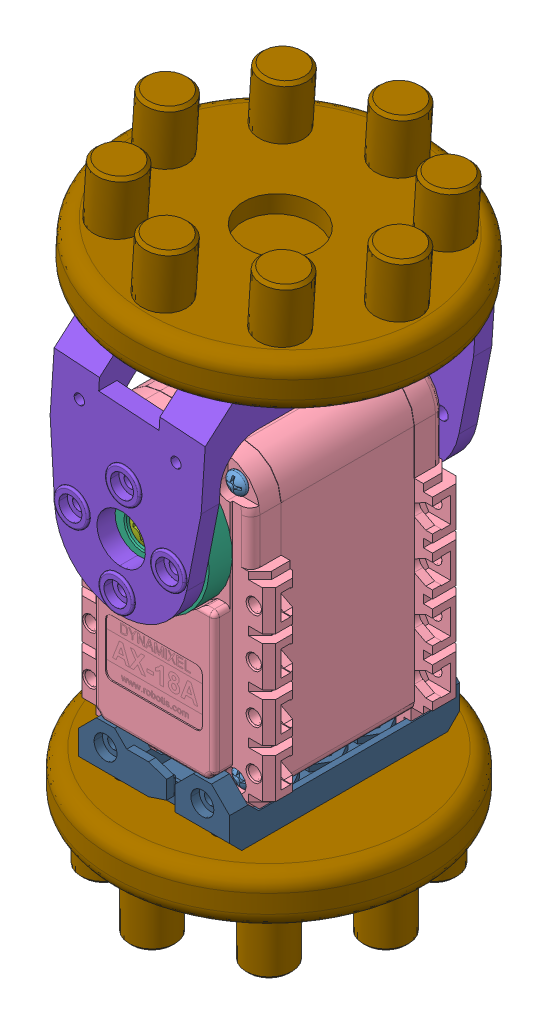
SolidWorks assembly joint, configuration Default. Lengths in mm.
Overall size (63.01 103.17 56.48).
16 component instances, 10 part files, 31 mates.
Components (placement in the parent):
- Cover Screws^joint-8: Cover Screws^joint [Défaut] at (-252.3267 41.8937 41.7384) x (0 1 0) z (1 0 0) size (3.5 30.7 3.5) (virtual)
- Insert M3^joint-2: Insert M3^joint [Défaut] at (-242.8267 33.3937 8.8384) x (-1 0 0) z (0 1 0) size (4.98 7 4.98) (virtual)
- Cover Screws^joint-9: Cover Screws^joint [Défaut] at (-232.3267 0.3937 41.7384) x (0 1 0) z (1 0 0) size (3.5 30.7 3.5) (virtual)
- 3 Pins Connector^joint-3: 3 Pins Connector^joint [Défaut] at (-237.7767 18.2037 17.4884) x (1 0 0) z (0 1 0) size (9.9 9.43 4.9) (virtual)
- Cover Screws^joint-10: Cover Screws^joint [Défaut] at (-233.3267 41.8937 41.7384) x (0 1 0) z (1 0 0) size (3.5 30.7 3.5) (virtual)
- 3 Pins Connector^joint-4: 3 Pins Connector^joint [Défaut] at (-247.7767 18.2037 17.4884) x (1 0 0) z (0 1 0) size (9.9 9.43 4.9) (virtual)
- Body^joint-2: Body^joint [Défaut] at (-242.8267 33.3937 27.2384) size (32 50.04 38.37) (virtual)
- Horn Assembly^joint-2: Horn Assembly^joint [Default] at (-242.8267 33.3937 48.1184) x (-1 0 0) z (0 0 1) size (22 22 9.6) (virtual)
  - Wheel Gear^Horn Assembly_joint-1: Wheel Gear^Horn Assembly_joint [Défaut] at (0 0 -22.94) size (6.5 6.5 5.51) (virtual)
  - Horn^Horn Assembly_joint-1: Horn^Horn Assembly_joint [Défaut] at (0 0 -1.84) x (0 -1 0) z (0 0 1) size (22 22 6.7) (virtual)
  - BHS M2x8^Horn Assembly_joint-1: BHS M2x8^Horn Assembly_joint [Défaut] at (0 0 -1.39) x (1 0 0) z (0 -1 0) size (5.5 9.6 5.5) (virtual)
- Cover Screws^joint-11: Cover Screws^joint [Défaut] at (-253.3267 0.3937 41.7384) x (0 1 0) z (1 0 0) size (3.5 30.7 3.5) (virtual)
- FP04-F2.stp-3: FP04-F2.stp [Default] at (-243.3649 33.4118 27.1184) x (0 0 1) z (0.067269 0.997735 0) size (48.8 25 37)
- servo_module-8: servo_module [Default] at (-242.8267 -16.1063 27.2384) size (56.36 17 56.36)
- servo_module-9: servo_module [Default] at (-241.0777 67.3348 27.1184) x (-0.997735 0.067269 0) z (0 0 1) size (56.36 17 56.36)
- FP04-F3.stp-2: FP04-F3.stp [Default] at (-242.8267 -8.1063 27.2384) size (25 9 38)
Mates (geometry in assembly coordinates):
- Concentric29: concentric: cylinder of FP04-F2.stp-3 through (-233.634 58.8147 43.1184) axis (0.067269 0.997735 0) radius 1.05; cylinder of servo_module-9 through (-233.2304 64.8011 43.1184) axis (-0.067269 -0.997735 0) radius 1.15
- Distance4: distance = 1.88 mm aligned: plane of Horn Assembly^Dynamixel AX-18A-2/Horn^Horn Assembly_Dynamixel AX-18A-1 through (-242.8267 33.3937 48.1184) normal (0 0 1); plane of Body^Dynamixel AX-18A-2 through (-242.8267 33.3937 46.2384) normal (0 0 1)
- Concentric30: concentric anti-aligned: cylinder of Cover Screws^Dynamixel AX-18A-8 through (-252.3267 41.8937 42.9134) axis (0 0 -1) radius 0.8; cylinder of Body^Dynamixel AX-18A-2 through (-252.3267 41.8937 46.2384) axis (0 0 1) radius 1.035
- Concentric31: concentric anti-aligned: cylinder of Cover Screws^Dynamixel AX-18A-9 through (-232.3267 0.3937 42.9134) axis (0 0 -1) radius 0.8; cylinder of Body^Dynamixel AX-18A-2 through (-232.3267 0.3937 46.2384) axis (0 0 1) radius 1.035
- Concentric32: concentric anti-aligned: cylinder of Cover Screws^Dynamixel AX-18A-10 through (-233.3267 41.8937 42.9134) axis (0 0 -1) radius 0.8; cylinder of Body^Dynamixel AX-18A-2 through (-233.3267 41.8937 46.2384) axis (0 0 1) radius 1.035
- Concentric33: concentric anti-aligned: cylinder of Body^Dynamixel AX-18A-2 through (-253.3267 0.3937 46.2384) axis (0 0 1) radius 1.035; cylinder of Cover Screws^Dynamixel AX-18A-11 through (-253.3267 0.3937 42.9134) axis (0 0 -1) radius 0.8
- Concentric34: concentric anti-aligned: cylinder of Body^Dynamixel AX-18A-2 through (-242.8267 33.3937 43.6384) axis (0 0 1) radius 4.6; cone of Horn Assembly^Dynamixel AX-18A-2/Horn^Horn Assembly_Dynamixel AX-18A-1 through (-242.8267 33.3937 44.2784) axis (0 0 -1)
- LimitAngle1: limit planar angle = 0.100093 rad: plane of Horn Assembly^Dynamixel AX-18A-2/Horn^Horn Assembly_Dynamixel AX-18A-1 through (-243.0739 44.3909 48.2784) normal (1 0 0); plane of Body^Dynamixel AX-18A-2 through (-242.9267 40.1437 43.3384) normal (1 0 0)
- Concentric35: concentric anti-aligned: cylinder of servo_module-8 through (-234.8267 -14.1063 35.2384) axis (0 1 0) radius 1.15; cylinder of FP04-F3.stp-2 through (-234.8267 -8.1063 35.2384) axis (0 -1 0) radius 1.05
- Concentric36: concentric anti-aligned: cylinder of servo_module-8 through (-250.8267 -14.1063 19.2384) axis (0 1 0) radius 1.15; cylinder of FP04-F3.stp-2 through (-250.8267 -8.1063 19.2384) axis (0 -1 0) radius 1.05
- Concentric37: concentric anti-aligned: cylinder of Body^Dynamixel AX-18A-2 through (-250.8267 -2.6063 43.2384) axis (0 0 -1) radius 1.1; cylinder of FP04-F3.stp-2 through (-250.8267 -2.6063 46.2384) axis (0 0 1) radius 1.05
- Coincident16: coincident: point of Horn Assembly^Dynamixel AX-18A-2/Horn^Horn Assembly_Dynamixel AX-18A-1; cylinder of FP04-F2.stp-3 through (-243.903 25.4299 3.1184) axis (0 0 -1) radius 1.05
- Coincident17: coincident: plane of FP04-F2.stp-3 through (-229.1442 58.512 3.1184) normal (0.067269 0.997735 0); plane of servo_module-9 through (-241.6159 59.3529 27.1184) normal (-0.067269 -0.997735 0)
- Lock2: lock: unknown of 3 Pins Connector^joint-3; unknown of Body^joint-2
- Lock3: lock: unknown of 3 Pins Connector^joint-4; unknown of Body^joint-2
- Lock4: lock: unknown of Insert M3^joint-2; unknown of Body^joint-2
- Concentric38: concentric aligned: cylinder of Body^Dynamixel AX-18A-2 through (-234.8267 -2.6063 11.2384) axis (0 0 1) radius 1.1; cylinder of FP04-F3.stp-2 through (-234.8267 -2.6063 46.2384) axis (0 0 1) radius 1.05
- Concentric39: concentric: cylinder of FP04-F2.stp-3 through (-249.5978 59.891 43.1184) axis (0.067269 0.997735 0) radius 1.05; cylinder of servo_module-9 through (-249.1941 65.8774 43.1184) axis (-0.067269 -0.997735 0) radius 1.15
- Coincident18: coincident anti-aligned: plane of Cover Screws^Dynamixel AX-18A-10 through (-233.3267 41.8937 41.7384) normal (0 0 -1); plane of Body^Dynamixel AX-18A-2 through (-242.8267 33.3937 41.7384) normal (0 0 1)
- Coincident19: coincident anti-aligned: plane of Cover Screws^Dynamixel AX-18A-9 through (-232.3267 0.3937 41.7384) normal (0 0 -1); plane of Body^Dynamixel AX-18A-2 through (-242.8267 33.3937 41.7384) normal (0 0 1)
- Parallel11: parallel aligned: plane of Cover Screws^Dynamixel AX-18A-8 through (-251.094 41.6865 42.3384) normal (0 1 0); plane of Cover Screws^Dynamixel AX-18A-10 through (-232.094 41.6865 42.3384) normal (0 1 0)
- Parallel12: parallel aligned: plane of Cover Screws^Dynamixel AX-18A-8 through (-252.1196 43.1264 42.3384) normal (-1 0 0); plane of Body^Dynamixel AX-18A-2 through (-242.7267 40.1437 43.6384) normal (-1 0 0)
- Coincident20: coincident anti-aligned: plane of Cover Screws^Dynamixel AX-18A-8 through (-252.3267 41.8937 41.7384) normal (0 0 -1); plane of Body^Dynamixel AX-18A-2 through (-242.8267 33.3937 41.7384) normal (0 0 1)
- Coincident21: coincident anti-aligned: plane of Body^Dynamixel AX-18A-2 through (-242.8267 33.3937 41.7384) normal (0 0 1); plane of Cover Screws^Dynamixel AX-18A-11 through (-253.3267 0.3937 41.7384) normal (0 0 -1)
- Parallel13: parallel aligned: plane of Cover Screws^Dynamixel AX-18A-9 through (-231.094 0.1865 42.3384) normal (0 1 0); plane of Cover Screws^Dynamixel AX-18A-10 through (-232.094 41.6865 42.3384) normal (0 1 0)
- Parallel14: parallel aligned: plane of Cover Screws^Dynamixel AX-18A-9 through (-231.094 0.1865 42.3384) normal (0 1 0); plane of Cover Screws^Dynamixel AX-18A-11 through (-252.094 0.1865 42.3384) normal (0 1 0)
- Parallel15: parallel aligned: plane of Body^Dynamixel AX-18A-2 through (-242.9267 40.1437 43.3384) normal (1 0 0); plane of Horn Assembly^Dynamixel AX-18A-2/Horn^Horn Assembly_Dynamixel AX-18A-1 through (-243.0739 44.3909 48.2784) normal (1 0 0)
- Concentric40: concentric: cylinder of Horn Assembly^Dynamixel AX-18A-2/Horn^Horn Assembly_Dynamixel AX-18A-1 through (-242.8267 41.3937 48.2784) axis (0 0 1) radius 1.05; cylinder of FP04-F2.stp-3 through (-242.8267 41.3937 3.1184) axis (0 0 -1) radius 1.05
- Coincident22: coincident: plane of Horn Assembly^Dynamixel AX-18A-2/Horn^Horn Assembly_Dynamixel AX-18A-1 through (-242.8267 33.3937 48.1184) normal (0 0 1); plane of FP04-F2.stp-3 through (-243.3649 33.4118 48.1184) normal (0 0 -1)
- Coincident23: coincident anti-aligned: plane of servo_module-8 through (-242.8267 -8.1063 27.2384) normal (0 1 0); plane of FP04-F3.stp-2 through (-242.8267 -8.1063 27.2384) normal (0 -1 0)
- Coincident24: coincident anti-aligned: plane of Body^Dynamixel AX-18A-2 through (-242.8267 33.3937 43.2384) normal (0 0 1); plane of FP04-F3.stp-2 through (-230.3267 -5.1063 43.2384) normal (0 0 -1)
